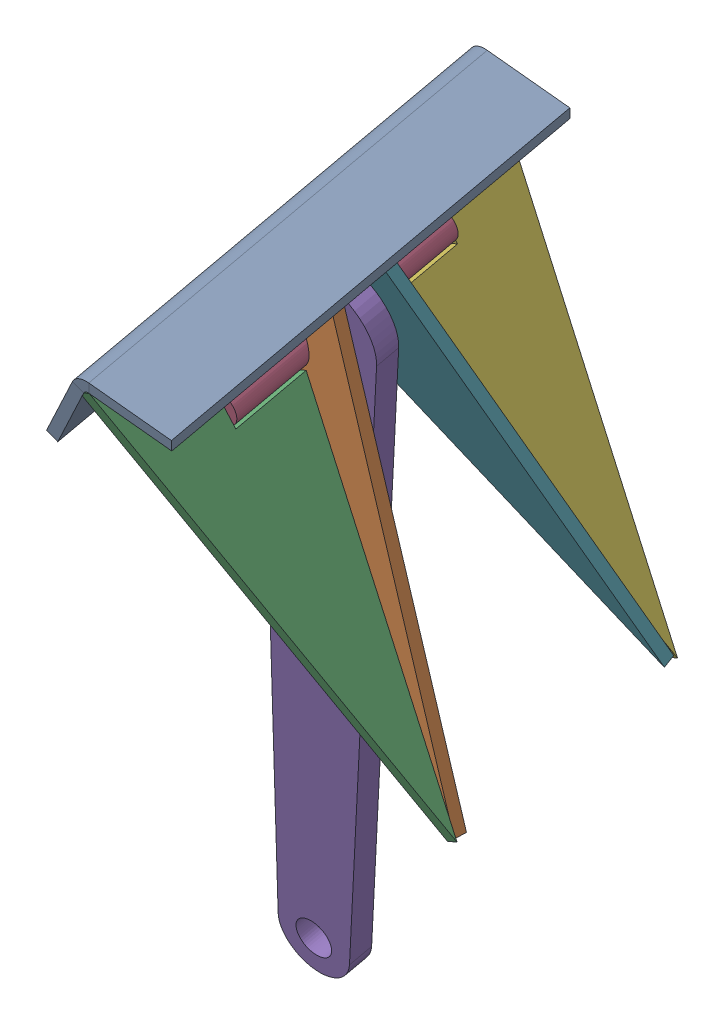
SolidWorks assembly anchor v1, configuration Défaut. Lengths in mm.
Overall size (368.42 732.42 430.09).
7 component instances, 7 part files, 11 mates.
Components (placement in the parent):
- cornière arrière-1: cornière arrière [Défaut] at (-154.1722 335.6049 251.9093) x (0.986703 -0.155237 -0.048155) z (-0.016629 0.198301 -0.98) size (107.36 78.6 360)
- gousset-2: gousset [Défaut] at (20.5601 -4.3945 97.6881) x (0.896877 0.436514 0.071175) z (-0.06997 -0.018861 0.997371) size (108.59 400 10)
- Pièce1-2: Pièce1 [Défaut] at (-148.0863 356.025 92.6727) x (0.016629 -0.198301 0.98) z (0.900996 0.427928 0.071302) size (160 392 10)
- axe-1: axe [Défaut] at (-123.0803 280.6745 158.79) x (-0.433508 0.881791 0.185785) z (-0.016629 0.198301 -0.98) size (30 30 200)
- bras-2: bras [Défaut] at (-66.6558 332.2532 76.2766) x (-0.979999 0.191161 0.05531) z (0.016629 -0.198301 0.98) size (97.19 680 20)
- SymétriePièce1-3: SymétriePièce1 [Défaut] at (-148.7514 363.957 53.4727) x (-0.016629 0.198301 -0.98) z (-0.900996 -0.427928 -0.071302) size (160 392 10)
- Symétriegousset-3: Symétriegousset [Défaut] at (17.2612 34.9451 -96.7269) x (0.896941 0.435763 0.07489) z (0.102564 -0.36981 0.923429) size (108.59 400 10)
Mates (geometry in assembly coordinates):
- Coïncidente11: coincident: plane of cornière arrière-1 through (-151.4398 402.2247 -102.0036) normal (0.871899 -0.476871 -0.111289); line of gousset-2 through (-153.4238 355.5939 82.2637) axis (-0.484193 -0.873503 -0.050487)
- Coïncidente13: coincident: cylinder of cornière arrière-1 through (-152.2205 390.8464 -104.2928) axis (0.016629 -0.198301 0.98) radius 5; point of gousset-2
- Coïncidente15: coincident: line of cornière arrière-1 through (-151.4121 395.6852 -103.3273) axis (0.016629 -0.198301 0.98); line of Pièce1-2 through (-148.0863 356.025 92.6727) axis (0.016629 -0.198301 0.98)
- Angle1: planar angle = 0.959931 rad: plane of Pièce1-2 through (-148.0863 356.025 92.6727) normal (0.900996 0.427928 0.071302); plane of cornière arrière-1 through (-161.7756 397.3157 -102.8216) normal (-0.161681 -0.96777 -0.193083)
- Coïncidente16: coincident: plane of cornière arrière-1 through (-150.5935 321.8422 249.0637) normal (0.016629 -0.198301 0.98); point of Pièce1-2
- Coïncidente17: coincident: plane of gousset-2 through (20.5601 -4.3945 97.6881) normal (-0.06997 -0.018861 0.997371); plane of Pièce1-2 through (-157.0962 351.7457 91.9596) normal (0.06997 0.018861 -0.997371)
- Coïncidente18: coincident: plane of Pièce1-2 through (-125.078 296.041 161.9333) normal (-0.016629 0.198301 -0.98); plane of axe-1 through (-123.0803 280.6745 158.79) normal (0.016629 -0.198301 0.98)
- Tangent3: tangent: plane of Pièce1-2 through (-126.242 309.9221 93.3333) normal (0.433508 -0.881791 -0.185785); cylinder of axe-1 through (-126.4062 320.3348 -37.21) axis (0.016629 -0.198301 0.98) radius 15
- Coïncidente21: coincident: plane of Pièce1-2 through (-157.0962 351.7457 91.9596) normal (-0.900996 -0.427928 -0.071302); plane of axe-1 through (-133.2542 290.3947 158.8887) normal (0.900996 0.427928 0.071302)
- Coaxiale4: concentric: cylinder of axe-1 through (-126.4062 320.3348 -37.21) axis (0.016629 -0.198301 0.98) radius 15; cylinder of bras-2 through (-124.9121 302.518 50.8401) axis (0.016629 -0.198301 0.98) radius 16
- Distance4: distance = 170 mm: plane of cornière arrière-1 through (-152.2205 390.8464 -104.2928) normal (-0.016629 0.198301 -0.98); plane of bras-2 through (-244.8873 -279.0799 -64.8095) normal (-0.016629 0.198301 -0.98)
